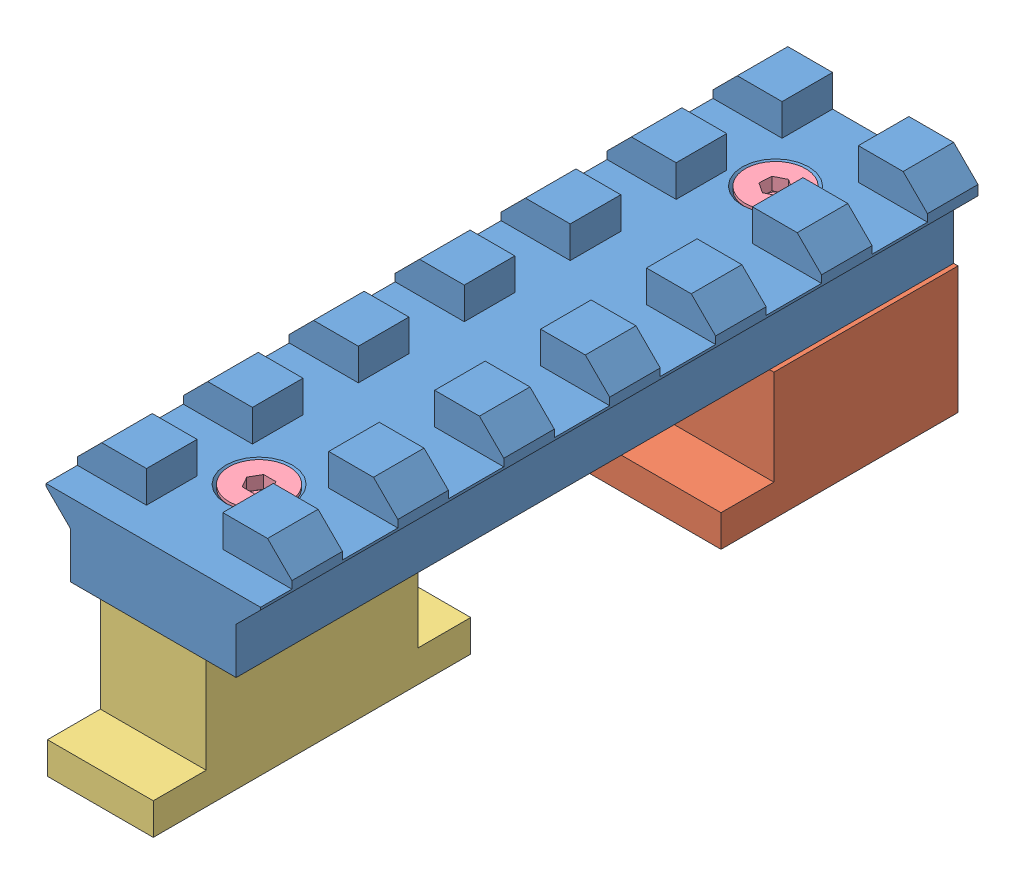
SolidWorks assembly Baugruppe1, configuration Standard. Lengths in mm.
Overall size (20.27 21.9 72.8).
5 component instances, 4 part files, 10 mates.
Components (placement in the parent):
- Rail-3: Rail [Standard] at (-4.1271 5.1584 0) size (20.27 9.9 67.8)
- flip_back-3: flip_back [Standard] at (-4.1271 -4.7457 0) x (0 0 1) z (-1 0 0) size (22.4 12 16.5)
- flip_front-1: flip_front [Standard] at (-4.1271 -4.7457 57.8) x (0 0 -1) z (1 0 0) size (30 12 10)
- Socket Countersunk Head Screw_DIN-2: Socket Countersunk Head Screw_DIN [DIN 7991 - M3 x 16 --- 12.8S] at (-4.1271 2.1584 57.8) x (0 -1 0) z (0 0 1) size (16 5.7 5.7)
- Socket Countersunk Head Screw_DIN-3: Socket Countersunk Head Screw_DIN [DIN 7991 - M3 x 16 --- 12.8S] at (-4.1271 2.1584 9) x (0 -1 0) z (-0.546944 0 0.837169) size (16 5.7 5.7)
Mates (geometry in assembly coordinates):
- Deckungsgleich6: coincident: moEndPointRef_w of Rail-3; moEndPointRef_w of flip_back-3
- Deckungsgleich7: coincident anti-aligned: plane of Rail-3 through (-11.963 -4.7457 67.8) normal (0 -1 0); plane of flip_back-3 through (-12.3771 -4.7457 0) normal (0 1 0)
- Deckungsgleich8: coincident anti-aligned: line of Rail-3 through (-11.963 -4.7457 0) axis (1 0 0); line of flip_back-3 through (4.1229 -4.7457 0) axis (-1 0 0)
- Deckungsgleich9: coincident aligned: plane of Rail-3 through (-4.1271 12.9943 67.8) normal (0 0 1); plane of flip_front-1 through (0.8729 -13.7457 67.8) normal (0 0 1)
- Deckungsgleich10: coincident: moEndPointRef_w of flip_front-1; moEndPointRef_w of Rail-3
- Deckungsgleich11: coincident anti-aligned: plane of Rail-3 through (-11.963 -4.7457 67.8) normal (0 -1 0); plane of flip_front-1 through (0.8729 -4.7457 72.8) normal (0 1 0)
- Konzentrisch1: concentric aligned: cone of Rail-3 through (-4.1271 2.1584 9) axis (0 -1 0); cone of Socket Countersunk Head Screw_DIN-3 through (-4.1271 1.8084 9) axis (0 -1 0)
- Deckungsgleich12: coincident aligned: plane of Rail-3 through (-7.7316 2.1584 67.8) normal (0 1 0); plane of Socket Countersunk Head Screw_DIN-3 through (-4.1271 2.1584 9) normal (0 1 0)
- Konzentrisch3: concentric aligned: cone of Rail-3 through (-4.1271 2.1612 57.8) axis (0 -1 0); cone of Socket Countersunk Head Screw_DIN-2 through (-4.1271 1.8084 57.8) axis (0 -1 0)
- Deckungsgleich13: coincident aligned: plane of Rail-3 through (-7.7316 2.1584 67.8) normal (0 1 0); plane of Socket Countersunk Head Screw_DIN-2 through (-4.1271 2.1584 57.8) normal (0 1 0)
